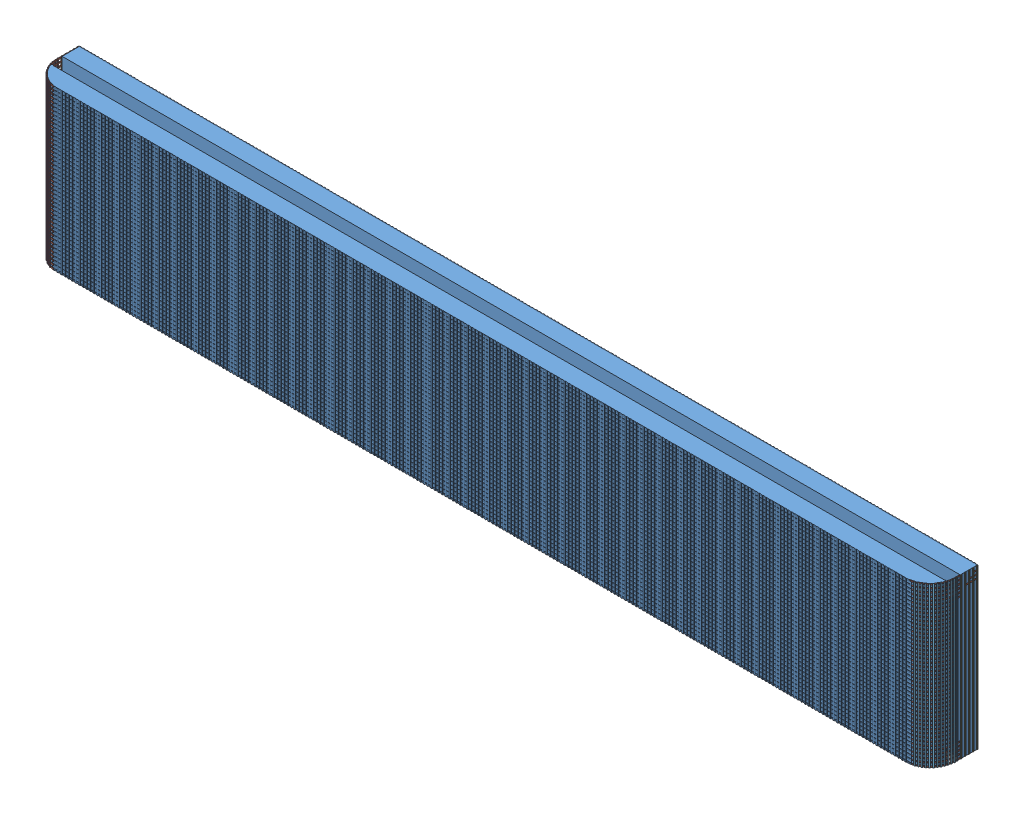
SolidWorks assembly B_neo_texture, configuration Default. Lengths in mm.
Overall size (450.61 79.89 24).
78 component instances, 5 part files, 16 mates.
Components (placement in the parent):
- B_neo_part1-1: B_neo_part1 [Default] at (-250.0255 -30.6599 18.4974) size (450 79.89 24)
- Part5^B_neo_texture-1: Part5^B_neo_texture [Default] at (-250.0255 49.2301 18.4974) x (1 0 0) z (0 1 0) size (450.2 23.6 0.6) (virtual)
- Part5^B_neo_texture-2: Part5^B_neo_texture [Default] at (-250.0255 47.4301 18.4974) x (1 0 0) z (0 1 0) size (450.2 23.6 0.6) (virtual)
- Part5^B_neo_texture-3: Part5^B_neo_texture [Default] at (-250.0255 45.6301 18.4974) x (1 0 0) z (0 1 0) size (450.2 23.6 0.6) (virtual)
- Part5^B_neo_texture-4: Part5^B_neo_texture [Default] at (-250.0255 43.8301 18.4974) x (1 0 0) z (0 1 0) size (450.2 23.6 0.6) (virtual)
- Part5^B_neo_texture-5: Part5^B_neo_texture [Default] at (-250.0255 42.0301 18.4974) x (1 0 0) z (0 1 0) size (450.2 23.6 0.6) (virtual)
- Part5^B_neo_texture-6: Part5^B_neo_texture [Default] at (-250.0255 40.2301 18.4974) x (1 0 0) z (0 1 0) size (450.2 23.6 0.6) (virtual)
- Part5^B_neo_texture-7: Part5^B_neo_texture [Default] at (-250.0255 38.4301 18.4974) x (1 0 0) z (0 1 0) size (450.2 23.6 0.6) (virtual)
- Part5^B_neo_texture-8: Part5^B_neo_texture [Default] at (-250.0255 36.6301 18.4974) x (1 0 0) z (0 1 0) size (450.2 23.6 0.6) (virtual)
- Part5^B_neo_texture-9: Part5^B_neo_texture [Default] at (-250.0255 34.8301 18.4974) x (1 0 0) z (0 1 0) size (450.2 23.6 0.6) (virtual)
- Part5^B_neo_texture-10: Part5^B_neo_texture [Default] at (-250.0255 33.0301 18.4974) x (1 0 0) z (0 1 0) size (450.2 23.6 0.6) (virtual)
- Part5^B_neo_texture-11: Part5^B_neo_texture [Default] at (-250.0255 31.2301 18.4974) x (1 0 0) z (0 1 0) size (450.2 23.6 0.6) (virtual)
- Part5^B_neo_texture-12: Part5^B_neo_texture [Default] at (-250.0255 29.4301 18.4974) x (1 0 0) z (0 1 0) size (450.2 23.6 0.6) (virtual)
- Part5^B_neo_texture-13: Part5^B_neo_texture [Default] at (-250.0255 27.6301 18.4974) x (1 0 0) z (0 1 0) size (450.2 23.6 0.6) (virtual)
- Part5^B_neo_texture-14: Part5^B_neo_texture [Default] at (-250.0255 25.8301 18.4974) x (1 0 0) z (0 1 0) size (450.2 23.6 0.6) (virtual)
- Part5^B_neo_texture-15: Part5^B_neo_texture [Default] at (-250.0255 24.0301 18.4974) x (1 0 0) z (0 1 0) size (450.2 23.6 0.6) (virtual)
- Part5^B_neo_texture-16: Part5^B_neo_texture [Default] at (-250.0255 22.2301 18.4974) x (1 0 0) z (0 1 0) size (450.2 23.6 0.6) (virtual)
- Part5^B_neo_texture-17: Part5^B_neo_texture [Default] at (-250.0255 20.4301 18.4974) x (1 0 0) z (0 1 0) size (450.2 23.6 0.6) (virtual)
- Part5^B_neo_texture-18: Part5^B_neo_texture [Default] at (-250.0255 18.6301 18.4974) x (1 0 0) z (0 1 0) size (450.2 23.6 0.6) (virtual)
- Part5^B_neo_texture-19: Part5^B_neo_texture [Default] at (-250.0255 16.8301 18.4974) x (1 0 0) z (0 1 0) size (450.2 23.6 0.6) (virtual)
- Part5^B_neo_texture-20: Part5^B_neo_texture [Default] at (-250.0255 15.0301 18.4974) x (1 0 0) z (0 1 0) size (450.2 23.6 0.6) (virtual)
- Part5^B_neo_texture-21: Part5^B_neo_texture [Default] at (-250.0255 13.2301 18.4974) x (1 0 0) z (0 1 0) size (450.2 23.6 0.6) (virtual)
- Part5^B_neo_texture-22: Part5^B_neo_texture [Default] at (-250.0255 11.4301 18.4974) x (1 0 0) z (0 1 0) size (450.2 23.6 0.6) (virtual)
- Part5^B_neo_texture-23: Part5^B_neo_texture [Default] at (-250.0255 9.6301 18.4974) x (1 0 0) z (0 1 0) size (450.2 23.6 0.6) (virtual)
- Part5^B_neo_texture-24: Part5^B_neo_texture [Default] at (-250.0255 7.8301 18.4974) x (1 0 0) z (0 1 0) size (450.2 23.6 0.6) (virtual)
- Part5^B_neo_texture-25: Part5^B_neo_texture [Default] at (-250.0255 6.0301 18.4974) x (1 0 0) z (0 1 0) size (450.2 23.6 0.6) (virtual)
- Part5^B_neo_texture-26: Part5^B_neo_texture [Default] at (-250.0255 4.2301 18.4974) x (1 0 0) z (0 1 0) size (450.2 23.6 0.6) (virtual)
- Part5^B_neo_texture-27: Part5^B_neo_texture [Default] at (-250.0255 2.4301 18.4974) x (1 0 0) z (0 1 0) size (450.2 23.6 0.6) (virtual)
- Part5^B_neo_texture-28: Part5^B_neo_texture [Default] at (-250.0255 0.6301 18.4974) x (1 0 0) z (0 1 0) size (450.2 23.6 0.6) (virtual)
- Part5^B_neo_texture-29: Part5^B_neo_texture [Default] at (-250.0255 -1.1699 18.4974) x (1 0 0) z (0 1 0) size (450.2 23.6 0.6) (virtual)
- Part5^B_neo_texture-30: Part5^B_neo_texture [Default] at (-250.0255 -2.9699 18.4974) x (1 0 0) z (0 1 0) size (450.2 23.6 0.6) (virtual)
- Part5^B_neo_texture-31: Part5^B_neo_texture [Default] at (-250.0255 -4.7699 18.4974) x (1 0 0) z (0 1 0) size (450.2 23.6 0.6) (virtual)
- Part5^B_neo_texture-32: Part5^B_neo_texture [Default] at (-250.0255 -6.5699 18.4974) x (1 0 0) z (0 1 0) size (450.2 23.6 0.6) (virtual)
- Part5^B_neo_texture-33: Part5^B_neo_texture [Default] at (-250.0255 -8.3699 18.4974) x (1 0 0) z (0 1 0) size (450.2 23.6 0.6) (virtual)
- Part5^B_neo_texture-34: Part5^B_neo_texture [Default] at (-250.0255 -10.1699 18.4974) x (1 0 0) z (0 1 0) size (450.2 23.6 0.6) (virtual)
- Part5^B_neo_texture-35: Part5^B_neo_texture [Default] at (-250.0255 -11.9699 18.4974) x (1 0 0) z (0 1 0) size (450.2 23.6 0.6) (virtual)
- Part5^B_neo_texture-36: Part5^B_neo_texture [Default] at (-250.0255 -13.7699 18.4974) x (1 0 0) z (0 1 0) size (450.2 23.6 0.6) (virtual)
- Part5^B_neo_texture-37: Part5^B_neo_texture [Default] at (-250.0255 -15.5699 18.4974) x (1 0 0) z (0 1 0) size (450.2 23.6 0.6) (virtual)
- Part5^B_neo_texture-38: Part5^B_neo_texture [Default] at (-250.0255 -17.3699 18.4974) x (1 0 0) z (0 1 0) size (450.2 23.6 0.6) (virtual)
- Part5^B_neo_texture-39: Part5^B_neo_texture [Default] at (-250.0255 -19.1699 18.4974) x (1 0 0) z (0 1 0) size (450.2 23.6 0.6) (virtual)
- Part5^B_neo_texture-40: Part5^B_neo_texture [Default] at (-250.0255 -20.9699 18.4974) x (1 0 0) z (0 1 0) size (450.2 23.6 0.6) (virtual)
- Part5^B_neo_texture-41: Part5^B_neo_texture [Default] at (-250.0255 -22.7699 18.4974) x (1 0 0) z (0 1 0) size (450.2 23.6 0.6) (virtual)
- Part5^B_neo_texture-42: Part5^B_neo_texture [Default] at (-250.0255 -24.5699 18.4974) x (1 0 0) z (0 1 0) size (450.2 23.6 0.6) (virtual)
- Part5^B_neo_texture-43: Part5^B_neo_texture [Default] at (-250.0255 -26.3699 18.4974) x (1 0 0) z (0 1 0) size (450.2 23.6 0.6) (virtual)
- Part5^B_neo_texture-44: Part5^B_neo_texture [Default] at (-250.0255 -28.1699 18.4974) x (1 0 0) z (0 1 0) size (450.2 23.6 0.6) (virtual)
- Part5^B_neo_texture-45: Part5^B_neo_texture [Default] at (-250.0255 -29.9699 18.4974) x (1 0 0) z (0 1 0) size (450.2 23.6 0.6) (virtual)
- Part6^B_neo_texture-1: Part6^B_neo_texture [Default] at (-250.0255 49.2301 18.4974) x (1 0 0) z (0 1 0) size (450.6 0.8 79.89) (virtual)
- Part6^B_neo_texture-2: Part6^B_neo_texture [Default] at (-250.0255 49.2301 20.4974) x (1 0 0) z (0 1 0) size (450.6 0.8 79.89) (virtual)
- Part6^B_neo_texture-3: Part6^B_neo_texture [Default] at (-250.0255 49.2301 22.4974) x (1 0 0) z (0 1 0) size (450.6 0.8 79.89) (virtual)
- Part6^B_neo_texture-4: Part6^B_neo_texture [Default] at (-250.0255 49.2301 24.4974) x (1 0 0) z (0 1 0) size (450.6 0.8 79.89) (virtual)
- Part6^B_neo_texture-5: Part6^B_neo_texture [Default] at (-250.0255 49.2301 26.4974) x (1 0 0) z (0 1 0) size (450.6 0.8 79.89) (virtual)
- Part6^B_neo_texture-6: Part6^B_neo_texture [Default] at (-250.0255 49.2301 28.4974) x (1 0 0) z (0 1 0) size (450.6 0.8 79.89) (virtual)
- Part7^B_neo_texture-1: Part7^B_neo_texture [Default] at (-250.0255 49.2301 28.4974) x (1 0 0) z (0 1 0) size (0.2 0.6 79.89) (virtual)
- Part7^B_neo_texture-2: Part7^B_neo_texture [Default] at (-247.592 49.2301 29.7325) x (0.994522 0 -0.104528) z (0 1 0) size (0.2 0.6 79.89) (virtual)
- Part7^B_neo_texture-3: Part7^B_neo_texture [Default] at (-245.0427 49.2301 30.7064) x (0.978148 0 -0.207912) z (0 1 0) size (0.2 0.6 79.89) (virtual)
- Part7^B_neo_texture-4: Part7^B_neo_texture [Default] at (-242.4055 49.2301 31.4085) x (0.951057 0 -0.309017) z (0 1 0) size (0.2 0.6 79.89) (virtual)
- Part7^B_neo_texture-5: Part7^B_neo_texture [Default] at (-239.7094 49.2301 31.8312) x (0.913545 0 -0.406737) z (0 1 0) size (0.2 0.6 79.89) (virtual)
- Part7^B_neo_texture-6: Part7^B_neo_texture [Default] at (-236.9839 49.2301 31.9696) x (0.866025 0 -0.5) z (0 1 0) size (0.2 0.6 79.89) (virtual)
- Part7^B_neo_texture-7: Part7^B_neo_texture [Default] at (-234.2588 49.2301 31.8224) x (0.809017 0 -0.587785) z (0 1 0) size (0.2 0.6 79.89) (virtual)
- Part7^B_neo_texture-8: Part7^B_neo_texture [Default] at (-231.5641 49.2301 31.3912) x (0.743145 0 -0.669131) z (0 1 0) size (0.2 0.6 79.89) (virtual)
- Part7^B_neo_texture-9: Part7^B_neo_texture [Default] at (-228.9292 49.2301 30.6807) x (0.669131 0 -0.743145) z (0 1 0) size (0.2 0.6 79.89) (virtual)
- Part7^B_neo_texture-10: Part7^B_neo_texture [Default] at (-226.383 49.2301 29.6986) x (0.587785 0 -0.809017) z (0 1 0) size (0.2 0.6 79.89) (virtual)
- Part7^B_neo_texture-11: Part7^B_neo_texture [Default] at (-223.9534 49.2301 28.4558) x (0.5 0 -0.866025) z (0 1 0) size (0.2 0.6 79.89) (virtual)
- Part7^B_neo_texture-12: Part7^B_neo_texture [Default] at (-221.667 49.2301 26.9658) x (0.406737 0 -0.913545) z (0 1 0) size (0.2 0.6 79.89) (virtual)
- Part7^B_neo_texture-13: Part7^B_neo_texture [Default] at (-219.5489 49.2301 25.245) x (0.309017 0 -0.951057) z (0 1 0) size (0.2 0.6 79.89) (virtual)
- Part8^B_neo_texture-1: Part8^B_neo_texture [Default] at (-250.0255 49.2301 28.4974) x (1 0 0) z (0 1 0) size (0.2 0.6 79.89) (virtual)
- Part8^B_neo_texture-2: Part8^B_neo_texture [Default] at (-249.9939 49.2301 -17.3053) x (0.994522 0 0.104528) z (0 1 0) size (0.2 0.6 79.89) (virtual)
- Part8^B_neo_texture-3: Part8^B_neo_texture [Default] at (-245.1748 49.2301 -62.8538) x (0.978148 0 0.207912) z (0 1 0) size (0.2 0.6 79.89) (virtual)
- Part8^B_neo_texture-4: Part8^B_neo_texture [Default] at (-235.621 49.2301 -107.6491) x (0.951057 0 0.309017) z (0 1 0) size (0.2 0.6 79.89) (virtual)
- Part8^B_neo_texture-5: Part8^B_neo_texture [Default] at (-221.4372 49.2301 -151.2003) x (0.913545 0 0.406737) z (0 1 0) size (0.2 0.6 79.89) (virtual)
- Part8^B_neo_texture-6: Part8^B_neo_texture [Default] at (-202.7786 49.2301 -193.0304) x (0.866025 0 0.5) z (0 1 0) size (0.2 0.6 79.89) (virtual)
- Part8^B_neo_texture-7: Part8^B_neo_texture [Default] at (-179.8499 49.2301 -232.6809) x (0.809017 0 0.587785) z (0 1 0) size (0.2 0.6 79.89) (virtual)
- Part8^B_neo_texture-8: Part8^B_neo_texture [Default] at (-152.9022 49.2301 -269.7176) x (0.743145 0 0.669131) z (0 1 0) size (0.2 0.6 79.89) (virtual)
- Part8^B_neo_texture-9: Part8^B_neo_texture [Default] at (-122.2307 49.2301 -303.7345) x (0.669131 0 0.743145) z (0 1 0) size (0.2 0.6 79.89) (virtual)
- Part8^B_neo_texture-10: Part8^B_neo_texture [Default] at (-88.1715 49.2301 -334.359) x (0.587785 0 0.809017) z (0 1 0) size (0.2 0.6 79.89) (virtual)
- Part8^B_neo_texture-11: Part8^B_neo_texture [Default] at (-51.0977 49.2301 -361.2557) x (0.5 0 0.866025) z (0 1 0) size (0.2 0.6 79.89) (virtual)
- Part8^B_neo_texture-12: Part8^B_neo_texture [Default] at (-11.4156 49.2301 -384.1297) x (0.406737 0 0.913545) z (0 1 0) size (0.2 0.6 79.89) (virtual)
- Part8^B_neo_texture-13: Part8^B_neo_texture [Default] at (30.4402 49.2301 -402.7305) x (0.309017 0 0.951057) z (0 1 0) size (0.2 0.6 79.89) (virtual)
Mates (geometry in assembly coordinates):
- InPlace1: in place: plane of B_neo_part1-1 through (199.9745 49.2301 3.7974) normal (0 1 0); plane of ? through (0 49.2301 0) normal (0 1 0); moOrthogonalPlaneRef_w of B_neo_part1-1 through (199.9745 49.2301 3.7974) normal (0 1 0); plane of ? through (0 49.2301 0) normal (0 0 -1); plane of B_neo_part1-1 through (199.9745 49.2301 3.7974) normal (0 1 0); plane of ? through (0 49.2301 0) normal (1 0 0); plane of B_neo_part1-1 through (199.9745 49.2301 3.7974) normal (0 1 0); unknown of ?
- Coincident1: coincident aligned: plane of ?; plane of ?
- Coincident2: coincident aligned: moOrthogonalPlaneRef_w of B_neo_part1-1 through (-250.0255 49.2301 18.4974) normal (0 0 -1); plane of Part5^Assem3-1 through (-250.0255 49.2301 18.4974) normal (0 0 -1)
- Coincident3: coincident anti-aligned: moOrthogonalPlaneRef_w of B_neo_part1-1 through (-250.0255 49.2301 18.4974) normal (-1 0 0); plane of Part5^Assem3-1 through (-250.0255 49.2301 18.4974) normal (1 0 0)
- InPlace2: in place: plane of ? through (-237.0255 49.2301 5.8974) normal (0 1 0); plane of ? through (0 49.2301 0) normal (0 1 0); plane of ? through (-237.0255 49.2301 5.8974) normal (0 1 0); plane of ? through (0 49.2301 0) normal (0 0 -1); plane of ? through (-237.0255 49.2301 5.8974) normal (0 1 0); plane of ? through (0 49.2301 0) normal (1 0 0); plane of ? through (-237.0255 49.2301 5.8974) normal (0 1 0); unknown of ?
- Coincident4: coincident aligned: plane of ?; plane of ?
- Coincident5: coincident aligned: moOrthogonalPlaneRef_w of Part5^B_neo_texture-1 through (-250.0255 49.2301 18.4974) normal (0 0 -1); plane of Part6^B_neo_texture-1 through (-250.0255 49.2301 18.4974) normal (0 0 -1)
- Coincident6: coincident anti-aligned: moOrthogonalPlaneRef_w of Part5^B_neo_texture-1 through (-250.0255 49.2301 18.4974) normal (-1 0 0); plane of Part6^B_neo_texture-1 through (-250.0255 49.2301 18.4974) normal (1 0 0)
- InPlace3: in place: plane of ? through (-250.0255 49.2301 28.4974) normal (0 1 0); plane of ? through (0 49.2301 0) normal (0 1 0); plane of ? through (-250.0255 49.2301 28.4974) normal (0 1 0); plane of ? through (0 49.2301 0) normal (0 0 -1); plane of ? through (-250.0255 49.2301 28.4974) normal (0 1 0); plane of ? through (0 49.2301 0) normal (1 0 0); plane of ? through (-250.0255 49.2301 28.4974) normal (0 1 0); unknown of ?
- Coincident7: coincident aligned: plane of ?; plane of ?
- Coincident8: coincident aligned: moOrthogonalPlaneRef_w of Part6^B_neo_texture-6 through (-250.0255 49.2301 28.4974) normal (0 0 -1); plane of Part7^B_neo_texture-1 through (-250.0255 49.2301 28.4974) normal (0 0 -1)
- Coincident9: coincident anti-aligned: moOrthogonalPlaneRef_w of Part6^B_neo_texture-6 through (-250.0255 49.2301 28.4974) normal (-1 0 0); plane of Part7^B_neo_texture-1 through (-250.0255 49.2301 28.4974) normal (1 0 0)
- InPlace4: in place: plane of ? through (-250.0255 49.2301 28.4974) normal (0 1 0); plane of ? through (0 49.2301 0) normal (0 1 0); plane of ? through (-250.0255 49.2301 28.4974) normal (0 1 0); plane of ? through (0 49.2301 0) normal (0 0 -1); plane of ? through (-250.0255 49.2301 28.4974) normal (0 1 0); plane of ? through (0 49.2301 0) normal (1 0 0); plane of ? through (-250.0255 49.2301 28.4974) normal (0 1 0); unknown of ?
- Coincident10: coincident aligned: plane of ?; plane of ?
- Coincident11: coincident aligned: moOrthogonalPlaneRef_w of Part6^B_neo_texture-6 through (-250.0255 49.2301 28.4974) normal (0 0 -1); plane of Part8^B_neo_texture-1 through (-250.0255 49.2301 28.4974) normal (0 0 -1)
- Coincident12: coincident anti-aligned: moOrthogonalPlaneRef_w of Part6^B_neo_texture-6 through (-250.0255 49.2301 28.4974) normal (-1 0 0); plane of Part8^B_neo_texture-1 through (-250.0255 49.2301 28.4974) normal (1 0 0)
